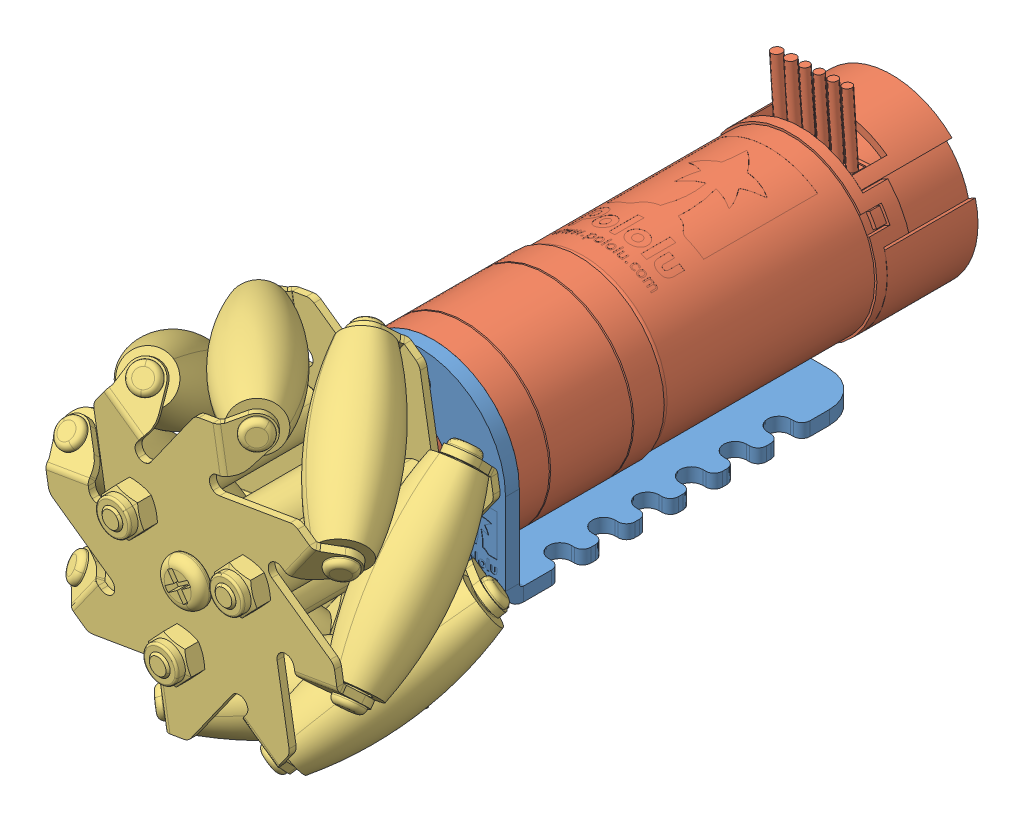
SolidWorks assembly Motor_Assembly, configuration Default. Lengths in mm.
Overall size (66.93 66.93 105.45).
4 component instances, 4 part files, 5 mates.
Components (placement in the parent):
- pololu-25d-mm-metal-gearmotor-bracket.step-1: pololu-25d-mm-metal-gearmotor-bracket.step [Default] at (22.2155 27.3731 38.2734) size (25 27 52)
- 25d-metal-gearmotor-34-47-encoder.step-1: 25d-metal-gearmotor-34-47-encoder.step [Default] at (21.2155 28.3731 50.7734) size (25 30.75 78.95)
- 48MM Steel Mecanum Wheel2-1: 48MM Steel Mecanum Wheel2 [Default] at (-15.358 23.7538 36.4991) x (0 0 1) z (0.578972 0.815347 0) size (35.5 48 48)
- hex screw_am-1: hex screw_am [B18.6.7M - M2.5 x 0.45 x 3 Indented HHMS --3N] at (21.4481 34.8545 57.659) x (-0.070518 -0.997511 -0.000043) z (-0.2808 0.019809 0.959562) size (5.1 4.62 4)
Mates (geometry in assembly coordinates):
- Coincident1: coincident anti-aligned: plane of pololu-25d-mm-metal-gearmotor-bracket.step-1 through (33.7155 15.8731 50.7734) normal (0 0 -1); plane of 25d-metal-gearmotor-34-47-encoder.step-1 through (21.2155 28.3731 50.7734) normal (0 0 1)
- Concentric1: concentric aligned: cylinder of pololu-25d-mm-metal-gearmotor-bracket.step-1 through (21.2155 28.3731 50.7734) axis (0 0 -1) radius 3.75; cylinder of 25d-metal-gearmotor-34-47-encoder.step-1 through (21.2155 28.3731 53.2734) axis (0 0 -1) radius 3.5
- Concentric3: concentric aligned: cylinder of 25d-metal-gearmotor-34-47-encoder.step-1 through (21.2155 28.3731 50.7734) axis (0 0 1) radius 2; cylinder of 48MM Steel Mecanum Wheel2-1 through (21.2155 28.3731 84.7734) axis (0 0 1) radius 1.65
- Distance1: distance = 1 mm anti-aligned: plane of 25d-metal-gearmotor-34-47-encoder.step-1 through (21.2155 28.3731 53.2734) normal (0 0 1); plane of 48MM Steel Mecanum Wheel2-1 through (21.2155 28.3731 54.2734) normal (0 0 -1)
- Tangent1: tangent: curve of 48MM Steel Mecanum Wheel2-1; circle of hex screw_am-1
